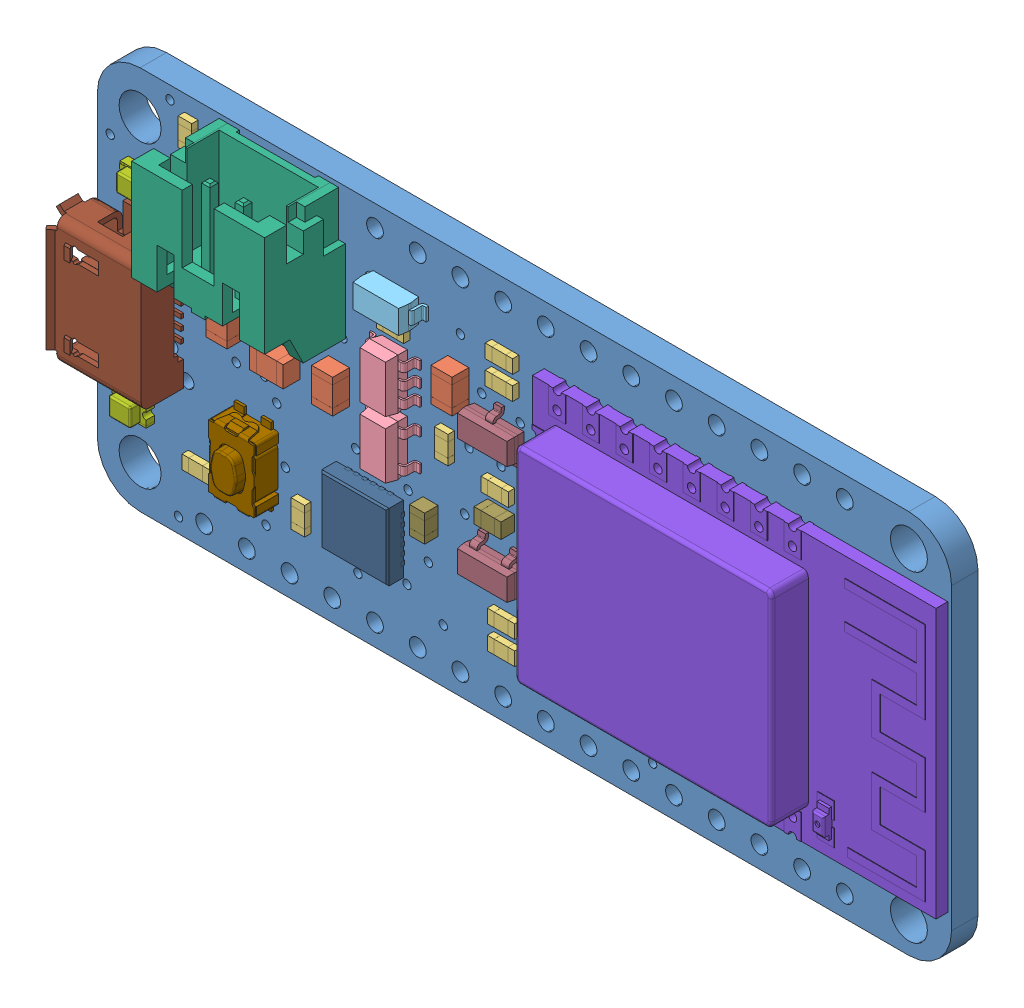
SolidWorks assembly 2821 Adafruit ESP8266 Feather, configuration Default. Lengths in mm.
Overall size (51.25 22.86 6.37).
31 component instances, 13 part files, 0 mates.
Components (placement in the parent):
- 2821 Adafruit ESP8266 Feather.step-1: 2821 Adafruit ESP8266 Feather.step [Default] at origin size (51.25 22.86 6.37)
  - PCB Component.step-1: PCB Component.step [Default] at origin size (51.25 22.86 6.37)
    - Board.step-1: Board.step [Default] at origin size (50.8 22.86 1.57)
    - 10uF.step-1: 10uF.step [Default] at (8.088 12.959 1.57) x (0 1 0) z (0 0 1) size (2 1.25 1)
    - 10uF.step-2: 10uF.step [Default] at (14.366 12.64 1.57) x (0 -1 0) z (0 0 1) size (2 1.25 1)
    - 10uF.step-3: 10uF.step [Default] at (11.049 12.192 1.57) x (-1 0 0) z (0 0 1) size (2 1.25 1)
    - 10uF.step-4: 10uF.step [Default] at (21.463 16.192 1.57) x (0 -1 0) z (0 0 1) size (2 1.25 1)
    - 10K.step-1: 10K.step [Default] at (12.302 4.775 1.57) x (0 -1 0) z (0 0 1) size (1.62 0.81 0.38)
    - 10K.step-2: 10K.step [Default] at (6.223 4.191 1.57) size (1.62 0.81 0.38)
    - 10K.step-3: 10K.step [Default] at (20.828 12.7 1.57) x (0 -1 0) z (0 0 1) size (1.62 0.81 0.38)
    - 10K.step-4: 10K.step [Default] at (24.257 18.923 1.57) x (-1 0 0) z (0 0 1) size (1.62 0.81 0.38)
    - 10K.step-5: 10K.step [Default] at (24.257 17.526 1.57) x (-1 0 0) z (0 0 1) size (1.62 0.81 0.38)
    - 10K.step-6: 10K.step [Default] at (24.384 3.937 1.57) size (1.62 0.81 0.38)
    - 10K.step-7: 10K.step [Default] at (24.384 5.334 1.57) x (-1 0 0) z (0 0 1) size (1.62 0.81 0.38)
    - 10K.step-8: 10K.step [Default] at (5.588 21.082 1.57) x (0 -1 0) z (0 0 1) size (1.62 0.81 0.38)
    - 10K.step-9: 10K.step [Default] at (24.003 11.938 1.57) x (-1 0 0) z (0 0 1) size (1.62 0.81 0.38)
    - 10K.step-10: 10K.step [Default] at (17.78 17.272 1.57) size (1.62 0.81 0.38)
    - MCP73831T-2ACI_OT.step-1: MCP73831T-2ACI_OT.step [Default] at (17.78 14.986 1.57) x (0 1 0) z (0 0 1) size (3 3 1.4)
    - MCP73831T-2ACI_OT.step-2: MCP73831T-2ACI_OT.step [Default] at (17.78 11.557 1.57) x (0 -1 0) z (0 0 1) size (3 3 1.4)
    - MBR120.step-1: MBR120.step [Default] at (17.907 18.796 1.57) x (-1 0 0) z (0 0 1) size (3.6 1.4 1.35)
    - JSTPH.step-1: JSTPH.step [Default] at (10.795 19.304 1.57) size (7.9 8.6 4.8)
    - RED.step-1: RED.step [Default] at (2.413 5.588 1.57) x (0 -1 0) z (0 0 1) size (1.25 2.02 1.1)
    - RED.step-2: RED.step [Default] at (2.858 17.336 1.57) x (0 -1 0) z (0 0 1) size (1.25 2.02 1.1)
    - ESP-12.step-1: ESP-12.step [Default] at (36.322 11.43 1.57) x (0 -1 0) z (0 0 1) size (16 24 2.95)
    - KMR2.step-1: KMR2.step [Default] at (9.398 6.35 1.57) x (0 -1 0) z (0 0 1) size (4.6 2.8 1.94)
    - CP2104.step-1: CP2104.step [Default] at (16.256 6.477 1.57) size (4 4 1)
    - 20329.step-1: 20329.step [Default] at (4.445 11.43 1.57) x (0 -1 0) z (0 0 1) size (8.8 5.6 3)
    - 1K.step-1: 1K.step [Default] at (24.003 10.541 1.57) size (1.6 0.9 0.8)
    - 1K.step-2: 1K.step [Default] at (19.812 8.382 1.57) x (0 -1 0) z (0 0 1) size (1.6 0.9 0.8)
    - mmbt2222.step-1: mmbt2222.step [Default] at (24.003 8.001 1.57) x (-1 0 0) z (0 0 1) size (3.04 2.64 1.12)
    - mmbt2222.step-2: mmbt2222.step [Default] at (24.003 14.986 1.57) size (3.04 2.64 1.12)
